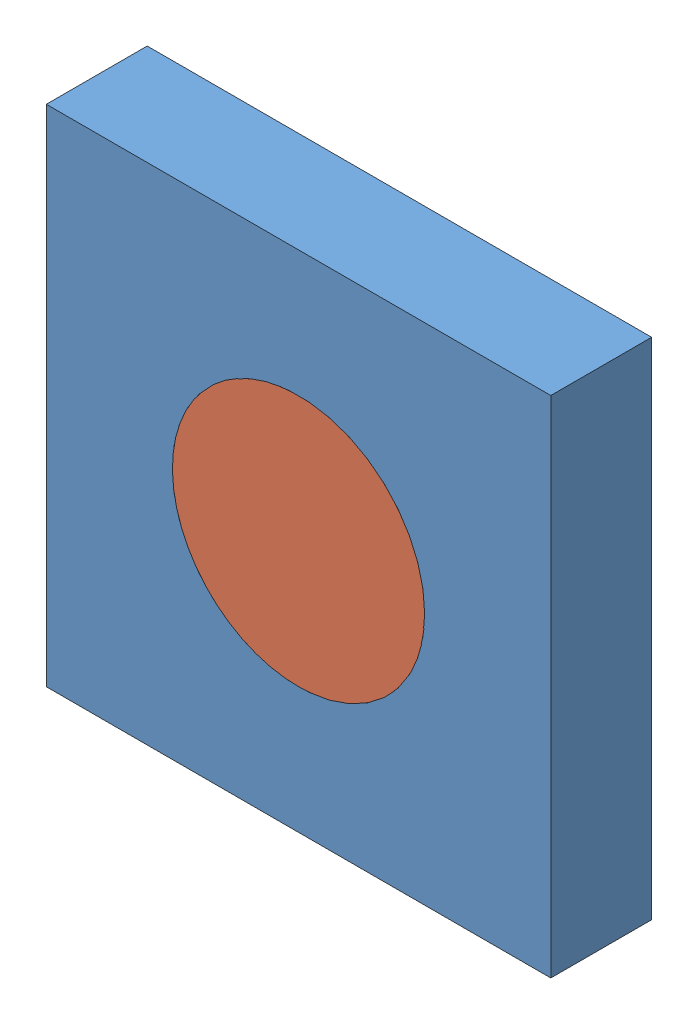
SolidWorks assembly Ass1, configuration Default. Lengths in mm.
Overall size (100 100 20).
2 component instances, 2 part files, 1 mates.
Components (placement in the parent):
- C1-1: C1 [Default] at origin size (100 100 20)
- cylindre-2: cylindre [Default] x (-0.812765 -0.582591 0) z (0 0 1) size (50 50 20)
Mates (geometry in assembly coordinates):
- Coincident1: coincident aligned: circle of C1-1; circle of cylindre-2
